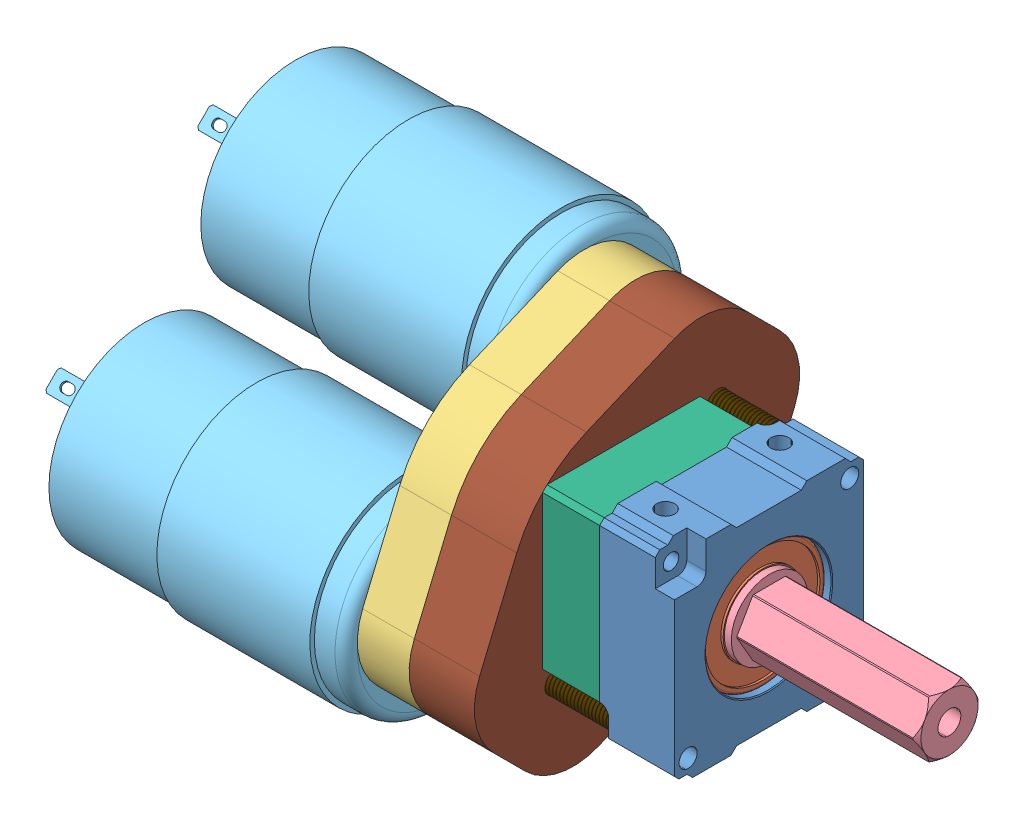
SolidWorks assembly Assem7, configuration Default. Lengths in mm.
Overall size (170.65 99.81 99.81).
43 component instances, 23 part files, 11 mates.
Components (placement in the parent):
- v2-VersaPlanetary-1stage-with-775pro-20161031-1: v2-VersaPlanetary-1stage-with-775pro-20161031 [Default] at (15.4912 42.8762 87.3765) size (71.25 44.45 42)
  - 217-2625-026 Rev1-1: 217-2625-026 Rev1 [Default] at (-6.2575 -5.0341 -38.5492) x (0 -1 0) z (-1 0 0) size (44.45 42 18.13)
  - 217-2742-001 Rev4-1: 217-2742-001 Rev4 [Default] at (-0.4115 -5.0341 -38.5492) x (1 0 0) z (0 0.976211 0.216822) size (7 28 28)
  - 217-2742-001 Rev4-2: 217-2742-001 Rev4 [Default] at (8.4427 -5.0341 -38.5492) size (7 28 28)
  - 217-2625-017 Rev1_9714K61-1: 217-2625-017 Rev1_9714K61 [Default] at (8.4427 -5.0341 -38.5492) x (0 0.932853 -0.360257) z (0 0.360257 0.932853) size (28.51 4.98 30.18)
  - 217-2625-003 Rev1-1: 217-2625-003 Rev1 [Default] at (7.2409 -5.0341 -38.5492) x (0 -1 0) z (1 0 0) size (17 17 64.12)
  - 217-2625-018 Rev1_98541A410-1: 217-2625-018 Rev1_98541A410 [Default] at (-0.9115 -4.635 -38.5422) x (1 0 0) z (0 -0.017452 0.999848) size (1 19.6 17.4)
  - 217-2816-001 Rev1-1: 217-2816-001 Rev1 [Default] at (-6.1075 -5.0341 -38.5492) x (0 -1 0) z (1 0 0) size (42 42 14.5)
- 217-2820 Rev1_Public-1: 217-2820 Rev1_Public [Default] at (10.7297 37.8421 48.8273) x (0 0 1) z (-1 0 0) size (39.26 38.9 17.4)
  - 217-2625-100-1: 217-2625-100 [Default] at origin size (39.26 38.9 12.7)
    - 217-2625-008 Rev1-1: 217-2625-008 Rev1 [Default] at origin size (34.7 34.7 4.7)
    - 217-2625-010 Rev1-1: 217-2625-010 Rev1 [Default] at (0 10.193 3.65) x (0.999813 0.019336 0) z (0 0 1) size (4 4 12)
    - 217-2625-010 Rev1-2: 217-2625-010 Rev1 [Default] at (8.691 -5.3258 3.65) size (4 4 12)
    - 217-2625-010 Rev1-3: 217-2625-010 Rev1 [Default] at (-8.691 -5.3258 3.65) size (4 4 12)
    - 217-2625-005 Rev1_Planet_Revolving_Follower01-1: 217-2625-005 Rev1_Planet_Revolving_Follower01 [Default] at (8.691 -5.3258 6.35) x (0.932816 0.360354 0) z (0 0 1) size (16.91 16.92 8)
    - 217-2625-005 Rev1_Planet_Revolving_Follower01-2: 217-2625-005 Rev1_Planet_Revolving_Follower01 [Default] at (-8.691 -5.3258 6.35) x (-0.932788 -0.360426 0) z (0 0 1) size (16.91 16.92 8)
    - 217-2625-005 Rev1_Planet_Revolving_Follower01-3: 217-2625-005 Rev1_Planet_Revolving_Follower01 [Default] at (0 10.193 6.35) x (0.893583 0.448898 0) z (0 0 1) size (16.91 16.92 8)
  - 217-2625-007 Rev1_Public-1: 217-2625-007 Rev1_Public [Default] at (0 0 6.7) x (0.992772 0.120019 0) z (0 0 1) size (14.49 14.49 12.72)
- 217-3141-1: 217-3141 [Default] at (-3.7162 65.5195 108.0661) x (0 0.707107 0.707107) z (0 0.707107 -0.707107) size (58 53.22 83.15)
  - 217-3141-001 Rev1-1: 217-3141-001 Rev1 [Default] at (-61.459 -0.0001 22.3173) x (0 0 1) z (-1 0 0) size (80 14.5 58)
  - 217-3141-007 Rev1_30T 32DP-1: 217-3141-007 Rev1_30T 32DP [Default] at (-61.459 -7.06 22.3173) x (0 -1 0) z (-0.999183 0 0.040426) size (22.38 25.55 25.47)
  - 217-3141-006 Rev1_30T 32DP-1: 217-3141-006 Rev1_30T 32DP [Default] at (-60.6253 -8.45 -1.5569) x (-0.491042 0 -0.871136) z (0 -1 0) size (25.47 25.55 10)
  - 217-3141-006 Rev1_30T 32DP-2: 217-3141-006 Rev1_30T 32DP [Default] at (-60.6253 -8.45 46.1914) x (-0.70455 0 0.709654) z (0 -1 0) size (25.47 25.55 10)
  - 217-2741-1: 217-2741 [Default] at (-61.459 2.75 22.3173) x (0 -1 0) z (-0.999445 0 -0.033298) size (5 26 26)
  - 217-2741-2: 217-2741 [Default] at (-61.459 -13.25 22.3173) x (0 -1 0) z (-0.537831 0 0.843053) size (5 26 26)
  - PINL-M020-006-S-1: PINL-M020-006-S [Default] at (-38.7145 5.7499 25.7357) x (0 1 0) z (-0.890225 0 0.455522) size (6 2 2)
  - SSS1032-0188-ZB-1: SSS1032-0188-ZB [Default] at (-62.5919 -10.325 -5.0458) x (0.78519 -0.43311 -0.442597) z (0.491042 0 0.871136) size (4.91 4.91 5.06)
  - SSS1032-0188-ZB-2: SSS1032-0188-ZB [Default] at (-63.447 -10.325 49.0336) x (0.387287 -0.837954 0.384502) z (0.70455 0 -0.709654) size (4.91 4.91 5.06)
  - NUT-832-NYLOCK-1: NUT-832-NYLOCK [Default] at (-42.215 -4.7501 20.2947) x (-0.913545 0 -0.406737) z (0.406737 0 -0.913545) size (10.2 4.9 8.12)
  - NUT-832-NYLOCK-2: NUT-832-NYLOCK [Default] at (-80.703 -4.7501 24.3399) x (0.912648 0 0.408747) z (-0.408747 0 0.912648) size (10.2 4.9 8.12)
  - 91251A346_91251A346-1: 91251A346_91251A346 [Default] at (-61.459 25.9749 47.7173) x (1 0 0) z (0 1 0) size (7.92 7.92 27.28)
  - 91251A346_91251A346-2: 91251A346_91251A346 [Default] at (-61.459 25.9749 -3.0827) x (1 0 0) z (0 1 0) size (7.92 7.92 27.28)
  - SSA_SSAM4-0010ZC-1: SSA_SSAM4-0010ZC [Default] at (-46.1253 -17.25 -1.5569) size (7 14 7)
  - SSA_SSA0832-0750ZC-1: SSA_SSA0832-0750ZC [Default] at (-80.703 -19.25 24.3399) x (-0.091926 0 -0.995766) z (-0.995766 0 0.091926) size (6.73 23.11 6.73)
  - SSA_SSA0832-0750ZC-2: SSA_SSA0832-0750ZC [Default] at (-42.215 -19.25 20.2947) x (-0.18632 0 -0.982489) z (-0.982489 0 0.18632) size (6.73 23.11 6.73)
  - SSA_SSAM4-0010ZC-2: SSA_SSAM4-0010ZC [Default] at (-75.1253 -17.25 46.1914) x (0.677756 0 0.735287) z (-0.735287 0 0.677756) size (7 14 7)
  - SSA_SSAM4-0010ZC-3: SSA_SSAM4-0010ZC [Default] at (-46.1253 -17.25 46.1914) x (0.994338 0 -0.106265) z (0.106265 0 0.994338) size (7 14 7)
  - SSA_SSAM4-0010ZC-4: SSA_SSAM4-0010ZC [Default] at (-75.1253 -17.25 -1.5569) x (0.537906 0 -0.843005) z (0.843005 0 0.537906) size (7 14 7)
  - 217-3141-004 Rev1-1: 217-3141-004 Rev1 [Default] at (-61.459 -13 22.3173) x (0 0 1) z (0 1 0) size (80 58 12.5)
  - 217-2625-013 Rev1-1: 217-2625-013 Rev1 [Default] at (-60.6253 -9.6 46.1914) x (1 0 0) z (0 1 0) size (8 7.93 7.5)
  - 217-2625-013 Rev1-2: 217-2625-013 Rev1 [Default] at (-60.6253 -9.6 -1.5569) x (1 0 0) z (0 1 0) size (8 7.93 7.5)
- 775 Pro-1: 775 Pro [Default] at (-22.9662 21.5501 66.2984) x (-1 0 0) z (0 -0.707107 0.707107) size (88 44.3 44.3)
- 775 Pro-2: 775 Pro [Default] at (-22.9662 55.3132 32.5353) x (-1 0 0) z (0 -0.707107 0.707107) size (88 44.3 44.3)
Mates (geometry in assembly coordinates):
- Concentric1: concentric: cylinder of v2-VersaPlanetary-1stage-with-775pro-20161031-1/217-2816-001 Rev1-1 through (15.7347 37.8421 48.8273) axis (-1 0 0) radius 19; cylinder of 217-2820 Rev1_Public-1/217-2625-100-1/217-2625-008 Rev1-1 through (8.3797 37.8421 48.8273) axis (1 0 0) radius 17.35
- Coincident1: coincident aligned: plane of v2-VersaPlanetary-1stage-with-775pro-20161031-1/217-2625-003 Rev1-1 through (8.3797 37.8421 48.8273) normal (-1 0 0); plane of 217-2820 Rev1_Public-1/217-2625-100-1/217-2625-008 Rev1-1 through (8.3797 37.8421 48.8273) normal (-1 0 0)
- Concentric2: concentric: cylinder of v2-VersaPlanetary-1stage-with-775pro-20161031-1/217-2816-001 Rev1-1 through (3.4837 37.8421 48.8273) axis (1 0 0) radius 20; cylinder of 217-3141-1/217-3141-001 Rev1-1 through (-47.7087 37.8421 48.8273) axis (1 0 0) radius 20
- Concentric3: concentric: cylinder of v2-VersaPlanetary-1stage-with-775pro-20161031-1/217-2625-026 Rev1-1 through (15.7337 55.8026 30.8668) axis (-1 0 0) radius 2.0193; circle of 217-3141-1/91251A346_91251A346-1
- Coincident2: coincident anti-aligned: plane of v2-VersaPlanetary-1stage-with-775pro-20161031-1/217-2816-001 Rev1-1 through (3.0337 16.8421 27.8273) normal (-1 0 0); plane of 217-3141-1/217-3141-001 Rev1-1 through (3.0337 37.8421 48.8273) normal (1 0 0)
- Concentric4: concentric: cylinder of 217-3141-1/217-2625-013 Rev1-1 through (-9.5662 55.3132 32.5353) axis (-1 0 0) radius 2.51; cylinder of 775 Pro-2 through (-22.9662 55.3132 32.5353) axis (1 0 0) radius 2.5
- Concentric5: concentric: cylinder of 217-3141-1/217-2625-013 Rev1-2 through (-9.5662 21.5501 66.2984) axis (-1 0 0) radius 2.51; cylinder of 775 Pro-1 through (-22.9662 21.5501 66.2984) axis (1 0 0) radius 2.5
- Concentric6: concentric: cylinder of 217-3141-1/SSA_SSAM4-0010ZC-2 through (-30.9662 45.0601 22.2822) axis (1 0 0) radius 2; cylinder of 775 Pro-2 through (-22.9662 45.0601 22.2822) axis (1 0 0) radius 1.65
- Concentric7: concentric: cylinder of 217-3141-1/SSA_SSAM4-0010ZC-4 through (-30.9662 11.297 56.0454) axis (1 0 0) radius 2; cylinder of 775 Pro-1 through (-22.9662 11.297 56.0454) axis (1 0 0) radius 1.65
- Coincident3: coincident anti-aligned: plane of 217-3141-1/217-3141-004 Rev1-1 through (-22.9662 37.8421 48.8273) normal (-1 0 0); plane of 775 Pro-2 through (-22.9662 49.0199 26.242) normal (1 0 0)
- Coincident4: coincident anti-aligned: plane of 217-3141-1/217-3141-004 Rev1-1 through (-22.9662 37.8421 48.8273) normal (-1 0 0); plane of 775 Pro-1 through (-22.9662 15.2568 60.0052) normal (1 0 0)
